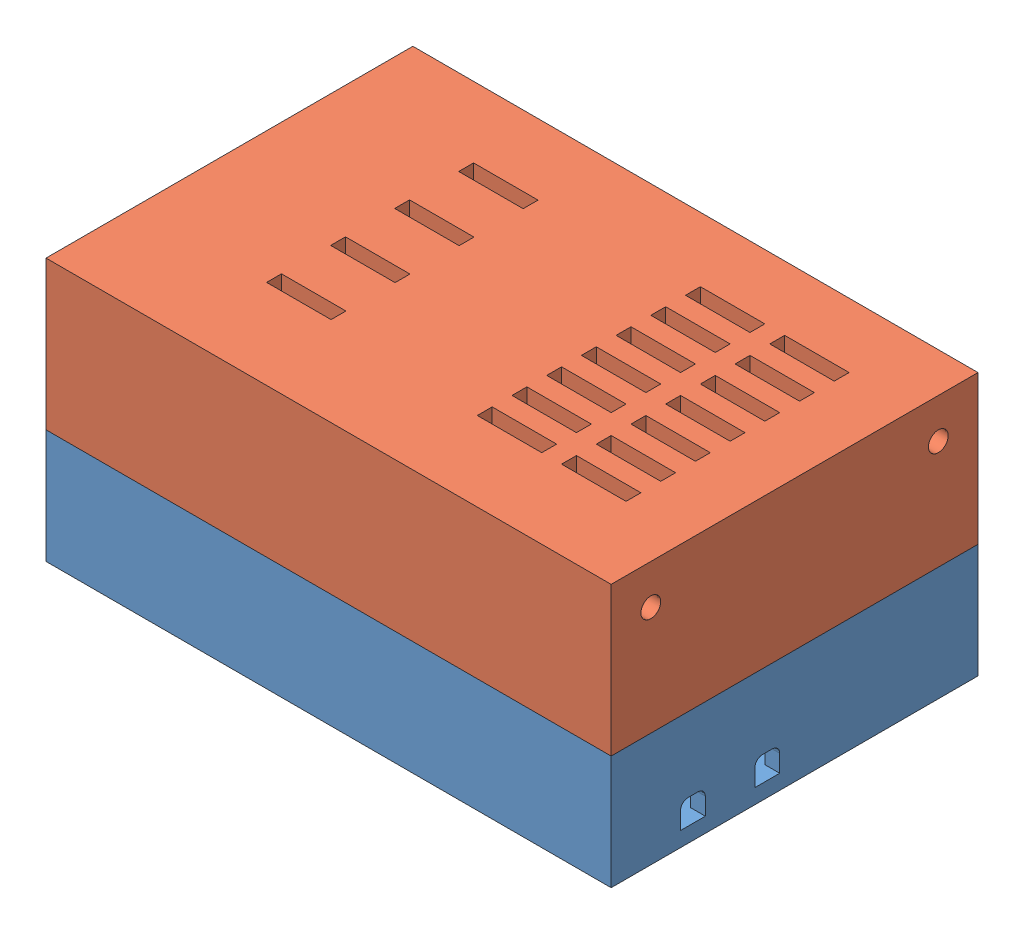
SolidWorks assembly box, configuration Valor predeterminado. Lengths in mm.
Overall size (114 53 74).
2 component instances, 2 part files, 4 mates.
Components (placement in the parent):
- button 2-1: button 2 [Valor predeterminado] at (-44.845 -17.9256 0) size (114 27 74)
- top-1: top [Valor predeterminado] at (-44.845 35.0744 0) x (1 0 0) z (0 0 -1) size (114 30 74)
Mates (geometry in assembly coordinates):
- Coincident1: coincident: plane of assembly; plane of assembly; plane of button 2-1 through (-101.845 -17.9256 37) normal (0 0 1); plane of top-1 through (12.155 35.0744 37) normal (0 0 1)
- Parallel1: parallel: plane of assembly; plane of assembly; plane of button 2-1 through (-44.845 -14.9256 0) normal (0 1 0); plane of top-1 through (-44.845 32.0744 0) normal (0 -1 0)
- Coincident3: coincident: plane of assembly; plane of assembly; plane of button 2-1 through (-101.845 -17.9256 -37) normal (-1 0 0); plane of top-1 through (-101.845 35.0744 37) normal (-1 0 0)
- Coincident4: coincident: plane of assembly; plane of assembly; plane of button 2-1 through (-44.845 5.0744 0) normal (0 1 0); plane of top-1 through (-44.845 5.0744 0) normal (0 -1 0)
